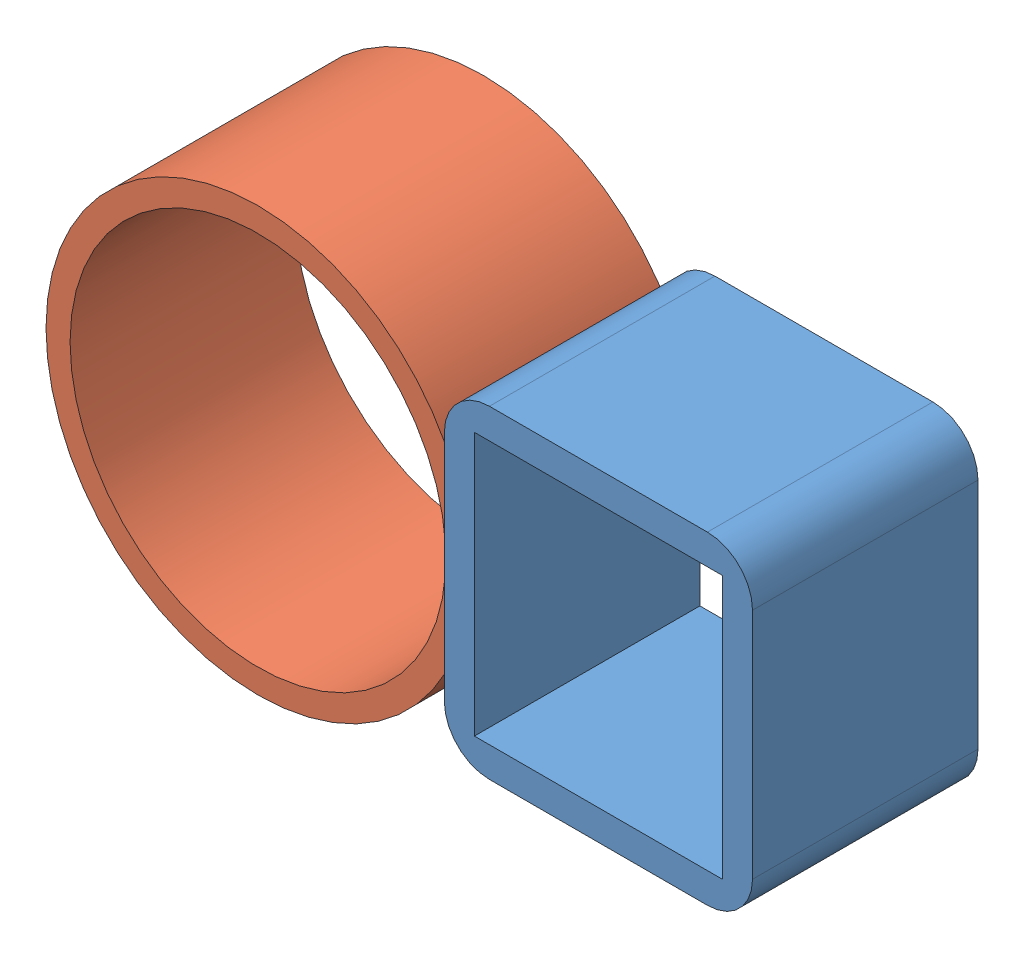
SolidWorks assembly portaanellodietro, configuration Default. Lengths in mm.
Overall size (47 28.2 15).
2 component instances, 2 part files, 1 mates.
Components (placement in the parent):
- portadevice-1: portadevice [Default] at (10.7552 15.391 10.2501) size (20.5 21.5 15)
- anello-1: anello [Default] at (-11.8926 15.9036 10.2501) x (0 1 0) z (1 0 0) size (28.2 15 28.2)
Mates (geometry in assembly coordinates):
- Coincident1: coincident aligned: plane of portadevice-1 through (10.7552 15.391 10.2501) normal (0 0 -1); plane of anello-1 through (-11.8926 15.9036 10.2501) normal (0 0 -1)
